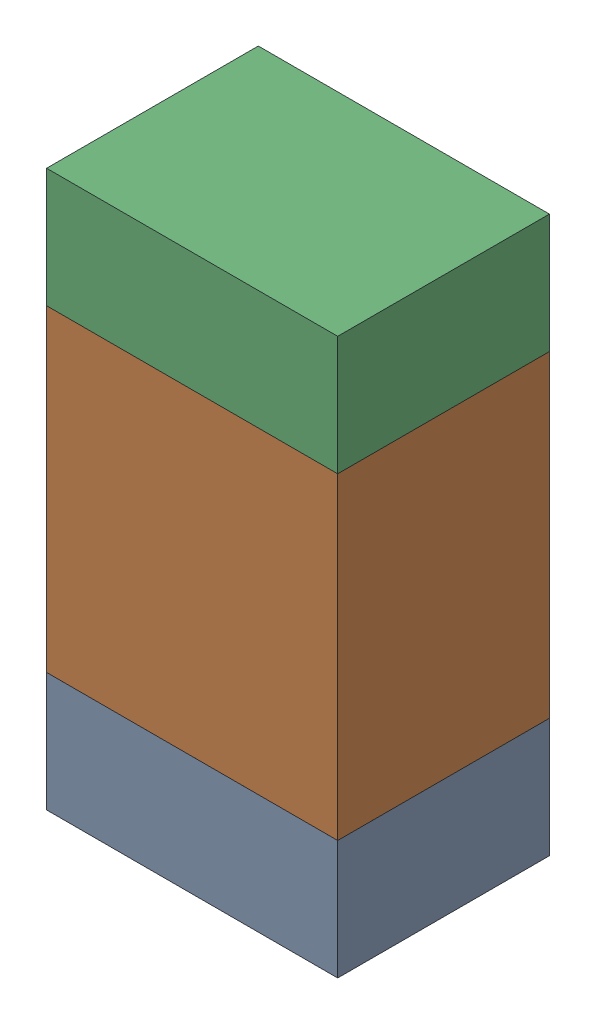
SolidWorks assembly R314_2PCB, configuration Default. Lengths in mm.
Overall size (0.55 1.05 0.4).
6 component instances, 2 part files, 0 mates.
Components (placement in the parent):
- 846483288-1: 846483288 [Default] at (133.4999 97.1874 -2.0638) size (0.55 0.22 0.4)
  - Extruded_12-1: Extruded_12 [Default] at origin size (0.55 0.22 0.4)
- 846483424-1: 846483424 [Default] at (133.4999 97.5999 -2.0638) size (0.55 0.6 0.4)
  - Extruded_13-1: Extruded_13 [Default] at origin size (0.55 0.6 0.4)
- 846483288-2: 846483288 [Default] at (133.4999 98.0124 -2.0638) size (0.55 0.22 0.4)
  - Extruded_12-1: Extruded_12 [Default] at origin size (0.55 0.22 0.4)
